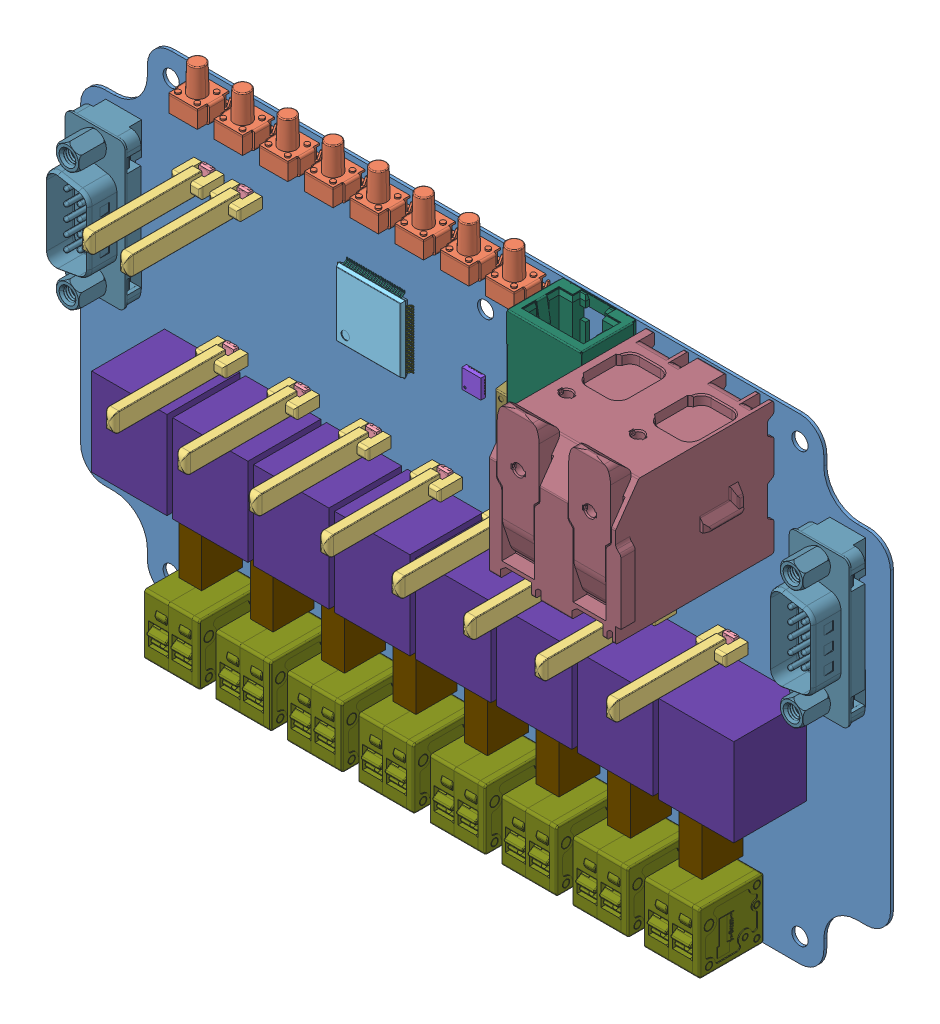
SolidWorks assembly KR-Df-01-EL-00 PCBA 2024_01_12_1, configuration Default. Lengths in mm.
Overall size (170 104.9 36.71).
192 component instances, 18 part files, 0 mates.
Components (placement in the parent):
- KR-Df-01-EL-00 PCBA 2024_01_12_1.step-1: KR-Df-01-EL-00 PCBA 2024_01_12_1.step [Default] at origin size (170 104.9 36.71)
  - Board.step-1: Board.step [Default] at origin size (170 100 0.62)
    - Open CASCADE STEP translator 7.5 3.1.1.step-1: Open CASCADE STEP translator 7.5 3.1.1.step [Default] at (0 0 -0.6237) size (170 100 0.62)
  - S607.step-1: S607.step [Default] at origin size (8.41 12.37 10.52)
    - 1-1825027-1.step-1: 1-1825027-1.step [Default] at (95 95.3 0) x (-1 0 0) z (0 1 0) size (8.41 10.52 12.37)
  - S606.step-1: S606.step [Default] at origin size (8.41 12.37 10.52)
    - 1-1825027-1.step-1: 1-1825027-1.step [Default] at (85.5 95.3 0) x (-1 0 0) z (0 1 0) size (8.41 10.52 12.37)
  - S605.step-1: S605.step [Default] at origin size (8.41 12.37 10.52)
    - 1-1825027-1.step-1: 1-1825027-1.step [Default] at (76 95.3 0) x (-1 0 0) z (0 1 0) size (8.41 10.52 12.37)
  - S604.step-1: S604.step [Default] at origin size (8.41 12.37 10.52)
    - 1-1825027-1.step-1: 1-1825027-1.step [Default] at (66.5 95.3 0) x (-1 0 0) z (0 1 0) size (8.41 10.52 12.37)
  - S603.step-1: S603.step [Default] at origin size (8.41 12.37 10.52)
    - 1-1825027-1.step-1: 1-1825027-1.step [Default] at (57 95.3 0) x (-1 0 0) z (0 1 0) size (8.41 10.52 12.37)
  - S602.step-1: S602.step [Default] at origin size (8.41 12.37 10.52)
    - 1-1825027-1.step-1: 1-1825027-1.step [Default] at (47.5 95.3 0) x (-1 0 0) z (0 1 0) size (8.41 10.52 12.37)
  - S601.step-1: S601.step [Default] at origin size (8.41 12.37 10.52)
    - 1-1825027-1.step-1: 1-1825027-1.step [Default] at (38 95.3 0) x (-1 0 0) z (0 1 0) size (8.41 10.52 12.37)
  - S600.step-1: S600.step [Default] at origin size (8.41 12.37 10.52)
    - 1-1825027-1.step-1: 1-1825027-1.step [Default] at (28.5 95.3 0) x (-1 0 0) z (0 1 0) size (8.41 10.52 12.37)
  - ME609.step-1: ME609.step [Default] at origin size (6.36 3.96 28.65)
    - BIVAR__INC_VLPR-24-1028-2_RGB8421504.step-1: BIVAR__INC_VLPR-24-1028-2_RGB8421504.step [Default] at (27 82 19.1) x (0 1 0) z (1 0 0) size (3.96 28.65 6.35)
  - ME608.step-1: ME608.step [Default] at origin size (6.36 3.96 28.65)
    - BIVAR__INC_VLPR-24-1028-2_RGB8421504.step-1: BIVAR__INC_VLPR-24-1028-2_RGB8421504.step [Default] at (35 82 19.1) x (0 1 0) z (1 0 0) size (3.96 28.65 6.35)
  - ME607.step-1: ME607.step [Default] at origin size (6.36 3.96 28.65)
    - BIVAR__INC_VLPR-24-1028-2_RGB8421504.step-1: BIVAR__INC_VLPR-24-1028-2_RGB8421504.step [Default] at (137 52 19.1) x (0 1 0) z (1 0 0) size (3.96 28.65 6.35)
  - ME606.step-1: ME606.step [Default] at origin size (6.36 3.96 28.65)
    - BIVAR__INC_VLPR-24-1028-2_RGB8421504.step-1: BIVAR__INC_VLPR-24-1028-2_RGB8421504.step [Default] at (122 52 19.1) x (0 1 0) z (1 0 0) size (3.96 28.65 6.35)
  - ME605.step-1: ME605.step [Default] at origin size (6.36 3.96 28.65)
    - BIVAR__INC_VLPR-24-1028-2_RGB8421504.step-1: BIVAR__INC_VLPR-24-1028-2_RGB8421504.step [Default] at (107 52 19.1) x (0 1 0) z (1 0 0) size (3.96 28.65 6.35)
  - ME604.step-1: ME604.step [Default] at origin size (6.36 3.96 28.65)
    - BIVAR__INC_VLPR-24-1028-2_RGB8421504.step-1: BIVAR__INC_VLPR-24-1028-2_RGB8421504.step [Default] at (92 52 19.1) x (0 1 0) z (1 0 0) size (3.96 28.65 6.35)
  - ME603.step-1: ME603.step [Default] at origin size (6.36 3.96 28.65)
    - BIVAR__INC_VLPR-24-1028-2_RGB8421504.step-1: BIVAR__INC_VLPR-24-1028-2_RGB8421504.step [Default] at (77 52 19.1) x (0 1 0) z (1 0 0) size (3.96 28.65 6.35)
  - ME602.step-1: ME602.step [Default] at origin size (6.36 3.96 28.65)
    - BIVAR__INC_VLPR-24-1028-2_RGB8421504.step-1: BIVAR__INC_VLPR-24-1028-2_RGB8421504.step [Default] at (62 52 19.1) x (0 1 0) z (1 0 0) size (3.96 28.65 6.35)
  - ME601.step-1: ME601.step [Default] at origin size (6.36 3.96 28.65)
    - BIVAR__INC_VLPR-24-1028-2_RGB8421504.step-1: BIVAR__INC_VLPR-24-1028-2_RGB8421504.step [Default] at (47 52 19.1) x (0 1 0) z (1 0 0) size (3.96 28.65 6.35)
  - ME600.step-1: ME600.step [Default] at origin size (6.36 3.96 28.65)
    - BIVAR__INC_VLPR-24-1028-2_RGB8421504.step-1: BIVAR__INC_VLPR-24-1028-2_RGB8421504.step [Default] at (32 52 19.1) x (0 1 0) z (1 0 0) size (3.96 28.65 6.35)
  - D609.step-1: D609.step [Default] at origin size (2.4 2.7 1.1)
    - IN-PI22TAT.step-1: IN-PI22TAT.step [Default] at (27 82 0) x (0 1 0) z (1 0 0) size (2.7 1.1 2.4)
  - D608.step-1: D608.step [Default] at origin size (2.4 2.7 1.1)
    - IN-PI22TAT.step-1: IN-PI22TAT.step [Default] at (35 82 0) x (0 1 0) z (1 0 0) size (2.7 1.1 2.4)
  - D607.step-1: D607.step [Default] at origin size (2.4 2.7 1.1)
    - IN-PI22TAT.step-1: IN-PI22TAT.step [Default] at (137 52 0) x (0 -1 0) z (-1 0 0) size (2.7 1.1 2.4)
  - D606.step-1: D606.step [Default] at origin size (2.4 2.7 1.1)
    - IN-PI22TAT.step-1: IN-PI22TAT.step [Default] at (122 52 0) x (0 -1 0) z (-1 0 0) size (2.7 1.1 2.4)
  - D605.step-1: D605.step [Default] at origin size (2.4 2.7 1.1)
    - IN-PI22TAT.step-1: IN-PI22TAT.step [Default] at (107 52 0) x (0 -1 0) z (-1 0 0) size (2.7 1.1 2.4)
  - D604.step-1: D604.step [Default] at origin size (2.4 2.7 1.1)
    - IN-PI22TAT.step-1: IN-PI22TAT.step [Default] at (92 52 0) x (0 -1 0) z (-1 0 0) size (2.7 1.1 2.4)
  - D603.step-1: D603.step [Default] at origin size (2.4 2.7 1.1)
    - IN-PI22TAT.step-1: IN-PI22TAT.step [Default] at (77 52 0) x (0 -1 0) z (-1 0 0) size (2.7 1.1 2.4)
  - D602.step-1: D602.step [Default] at origin size (2.4 2.7 1.1)
    - IN-PI22TAT.step-1: IN-PI22TAT.step [Default] at (62 52 0) x (0 -1 0) z (-1 0 0) size (2.7 1.1 2.4)
  - D601.step-1: D601.step [Default] at origin size (2.4 2.7 1.1)
    - IN-PI22TAT.step-1: IN-PI22TAT.step [Default] at (47 52 0) x (0 -1 0) z (-1 0 0) size (2.7 1.1 2.4)
  - D600.step-1: D600.step [Default] at origin size (2.4 2.7 1.1)
    - IN-PI22TAT.step-1: IN-PI22TAT.step [Default] at (32 52 0) x (0 -1 0) z (-1 0 0) size (2.7 1.1 2.4)
  - U500.step-1: U500.step [Default] at origin size (16 16 1.6)
    - STM32H573VIT6_RGB8421504.step-1: STM32H573VIT6_RGB8421504.step [Default] at (62 73 0) x (0 1 0) z (0 0 1) size (16 16 1.6)
      - Body.step-1: Body.step [Default] at origin size (14 14 1.5)
      - PinsArrayLR.step-1: PinsArrayLR.step [Default] at origin size (16 12.22 0.86)
      - PinsArrayTB.step-1: PinsArrayTB.step [Default] at origin size (12.22 16 0.86)
  - U200.step-1: U200.step [Default] at origin size (4 4 1)
    - 6102634304.step-1: 6102634304.step [Default] at (83 72 0) x (0 1 0) z (0 0 1) size (4 4 1)
      - Body-0.step-1: Body-0.step [Default] at (-2 -2 0) size (4 4 1)
        - Open CASCADE STEP translator 6.8 14.2.1.step-1: Open CASCADE STEP translator 6.8 14.2.1.step [Default] at origin size (4 4 1)
      - Pin_Shape.step-1: Pin_Shape.step [Default] at (-2 -1.37 0) size (0.4 0.24 0.2)
        - Open CASCADE STEP translator 6.8 14.4.1.step-1: Open CASCADE STEP translator 6.8 14.4.1.step [Default] at origin size (0.4 0.24 0.2)
      - Pin_Shape.step-2: Pin_Shape.step [Default] at (2 1.37 0) x (-1 0 0) z (0 0 1) size (0.4 0.24 0.2)
        - Open CASCADE STEP translator 6.8 14.4.1.step-1: Open CASCADE STEP translator 6.8 14.4.1.step [Default] at origin size (0.4 0.24 0.2)
      - Pin_Shape.step-3: Pin_Shape.step [Default] at (-2 -0.87 0) size (0.4 0.24 0.2)
        - Open CASCADE STEP translator 6.8 14.4.1.step-1: Open CASCADE STEP translator 6.8 14.4.1.step [Default] at origin size (0.4 0.24 0.2)
      - Pin_Shape.step-4: Pin_Shape.step [Default] at (2 0.87 0) x (-1 0 0) z (0 0 1) size (0.4 0.24 0.2)
        - Open CASCADE STEP translator 6.8 14.4.1.step-1: Open CASCADE STEP translator 6.8 14.4.1.step [Default] at origin size (0.4 0.24 0.2)
      - Pin_Shape.step-5: Pin_Shape.step [Default] at (-2 -0.37 0) size (0.4 0.24 0.2)
        - Open CASCADE STEP translator 6.8 14.4.1.step-1: Open CASCADE STEP translator 6.8 14.4.1.step [Default] at origin size (0.4 0.24 0.2)
      - Pin_Shape.step-6: Pin_Shape.step [Default] at (2 0.37 0) x (-1 0 0) z (0 0 1) size (0.4 0.24 0.2)
        - Open CASCADE STEP translator 6.8 14.4.1.step-1: Open CASCADE STEP translator 6.8 14.4.1.step [Default] at origin size (0.4 0.24 0.2)
      - Pin_Shape.step-7: Pin_Shape.step [Default] at (-2 0.13 0) size (0.4 0.24 0.2)
        - Open CASCADE STEP translator 6.8 14.4.1.step-1: Open CASCADE STEP translator 6.8 14.4.1.step [Default] at origin size (0.4 0.24 0.2)
      - Pin_Shape.step-8: Pin_Shape.step [Default] at (2 -0.13 0) x (-1 0 0) z (0 0 1) size (0.4 0.24 0.2)
        - Open CASCADE STEP translator 6.8 14.4.1.step-1: Open CASCADE STEP translator 6.8 14.4.1.step [Default] at origin size (0.4 0.24 0.2)
      - Pin_Shape.step-9: Pin_Shape.step [Default] at (-2 0.63 0) size (0.4 0.24 0.2)
        - Open CASCADE STEP translator 6.8 14.4.1.step-1: Open CASCADE STEP translator 6.8 14.4.1.step [Default] at origin size (0.4 0.24 0.2)
      - Pin_Shape.step-10: Pin_Shape.step [Default] at (2 -0.63 0) x (-1 0 0) z (0 0 1) size (0.4 0.24 0.2)
        - Open CASCADE STEP translator 6.8 14.4.1.step-1: Open CASCADE STEP translator 6.8 14.4.1.step [Default] at origin size (0.4 0.24 0.2)
      - Pin_Shape.step-11: Pin_Shape.step [Default] at (-2 1.13 0) size (0.4 0.24 0.2)
        - Open CASCADE STEP translator 6.8 14.4.1.step-1: Open CASCADE STEP translator 6.8 14.4.1.step [Default] at origin size (0.4 0.24 0.2)
      - Pin_Shape.step-12: Pin_Shape.step [Default] at (2 -1.13 0) x (-1 0 0) z (0 0 1) size (0.4 0.24 0.2)
        - Open CASCADE STEP translator 6.8 14.4.1.step-1: Open CASCADE STEP translator 6.8 14.4.1.step [Default] at origin size (0.4 0.24 0.2)
      - Pin_Shape.step-13: Pin_Shape.step [Default] at (-1.13 -2 0) x (0 1 0) z (0 0 1) size (0.4 0.24 0.2)
        - Open CASCADE STEP translator 6.8 14.4.1.step-1: Open CASCADE STEP translator 6.8 14.4.1.step [Default] at origin size (0.4 0.24 0.2)
      - Pin_Shape.step-14: Pin_Shape.step [Default] at (1.13 2 0) x (0 -1 0) z (0 0 1) size (0.4 0.24 0.2)
        - Open CASCADE STEP translator 6.8 14.4.1.step-1: Open CASCADE STEP translator 6.8 14.4.1.step [Default] at origin size (0.4 0.24 0.2)
      - Pin_Shape.step-15: Pin_Shape.step [Default] at (-0.63 -2 0) x (0 1 0) z (0 0 1) size (0.4 0.24 0.2)
        - Open CASCADE STEP translator 6.8 14.4.1.step-1: Open CASCADE STEP translator 6.8 14.4.1.step [Default] at origin size (0.4 0.24 0.2)
      - Pin_Shape.step-16: Pin_Shape.step [Default] at (0.63 2 0) x (0 -1 0) z (0 0 1) size (0.4 0.24 0.2)
        - Open CASCADE STEP translator 6.8 14.4.1.step-1: Open CASCADE STEP translator 6.8 14.4.1.step [Default] at origin size (0.4 0.24 0.2)
      - Pin_Shape.step-17: Pin_Shape.step [Default] at (-0.13 -2 0) x (0 1 0) z (0 0 1) size (0.4 0.24 0.2)
        - Open CASCADE STEP translator 6.8 14.4.1.step-1: Open CASCADE STEP translator 6.8 14.4.1.step [Default] at origin size (0.4 0.24 0.2)
      - Pin_Shape.step-18: Pin_Shape.step [Default] at (0.13 2 0) x (0 -1 0) z (0 0 1) size (0.4 0.24 0.2)
        - Open CASCADE STEP translator 6.8 14.4.1.step-1: Open CASCADE STEP translator 6.8 14.4.1.step [Default] at origin size (0.4 0.24 0.2)
      - Pin_Shape.step-19: Pin_Shape.step [Default] at (0.37 -2 0) x (0 1 0) z (0 0 1) size (0.4 0.24 0.2)
        - Open CASCADE STEP translator 6.8 14.4.1.step-1: Open CASCADE STEP translator 6.8 14.4.1.step [Default] at origin size (0.4 0.24 0.2)
      - Pin_Shape.step-20: Pin_Shape.step [Default] at (-0.37 2 0) x (0 -1 0) z (0 0 1) size (0.4 0.24 0.2)
        - Open CASCADE STEP translator 6.8 14.4.1.step-1: Open CASCADE STEP translator 6.8 14.4.1.step [Default] at origin size (0.4 0.24 0.2)
      - Pin_Shape.step-21: Pin_Shape.step [Default] at (0.87 -2 0) x (0 1 0) z (0 0 1) size (0.4 0.24 0.2)
        - Open CASCADE STEP translator 6.8 14.4.1.step-1: Open CASCADE STEP translator 6.8 14.4.1.step [Default] at origin size (0.4 0.24 0.2)
      - Pin_Shape.step-22: Pin_Shape.step [Default] at (-0.87 2 0) x (0 -1 0) z (0 0 1) size (0.4 0.24 0.2)
        - Open CASCADE STEP translator 6.8 14.4.1.step-1: Open CASCADE STEP translator 6.8 14.4.1.step [Default] at origin size (0.4 0.24 0.2)
      - Pin_Shape.step-23: Pin_Shape.step [Default] at (1.37 -2 0) x (0 1 0) z (0 0 1) size (0.4 0.24 0.2)
        - Open CASCADE STEP translator 6.8 14.4.1.step-1: Open CASCADE STEP translator 6.8 14.4.1.step [Default] at origin size (0.4 0.24 0.2)
      - Pin_Shape.step-24: Pin_Shape.step [Default] at (-1.37 2 0) x (0 -1 0) z (0 0 1) size (0.4 0.24 0.2)
        - Open CASCADE STEP translator 6.8 14.4.1.step-1: Open CASCADE STEP translator 6.8 14.4.1.step [Default] at origin size (0.4 0.24 0.2)
      - Open CASCADE STEP translator 6.8 14.1.step-1: Open CASCADE STEP translator 6.8 14.1.step [Default] at (-2 -2 0) size (0.51 0.51 0.01)
      - Thermal_Shape.step-1: Thermal_Shape.step [Default] at (-1.25 -1.25 -0.001) size (2.5 2.5 0)
  - T200.step-1: T200.step [Default] at origin size (9.3 12.8 5.68)
    - PT61018PEL.step-1: PT61018PEL.step [Default] at (99.35 78.3999 5.65) x (0 -1 0) z (1 0 0) size (12.8 5.68 9.3)
  - J400.step-1: J400.step [Default] at origin size (27.81 32.01 33.2)
    - 2616-1352.step-1: 2616-1352.step [Default] at (120.5 89.5 0) x (0 1 0) z (1 0 0) size (32.01 33.2 27.81)
  - J301.step-1: J301.step [Default] at origin size (12.55 30.81 15.4)
    - L717TSEH09POL2RM8--3DModel-STEP-533217.step-1: L717TSEH09POL2RM8--3DModel-STEP-533217.step [Default] at (167.275 53.58 0) x (0 1 0) z (1 0 0) size (30.81 15.4 12.55)
  - J300.step-1: J300.step [Default] at origin size (12.55 30.81 15.4)
    - L717TSEH09POL2RM8--3DModel-STEP-533217.step-1: L717TSEH09POL2RM8--3DModel-STEP-533217.step [Default] at (15.275 53.58 0) x (0 1 0) z (1 0 0) size (30.81 15.4 12.55)
  - P200.step-1: P200.step [Default] at origin size (16.33 18.55 13.95)
    - M-RJLSE-4X381-01T-REVT1.step-1: M-RJLSE-4X381-01T-REVT1.step [Default] at (108.9999 99.725 0) x (1 0 0) z (0 1 0) size (16.33 13.95 18.55)
  - P103.step-1: P103.step [Default] at origin size (11.62 12.71 17.41)
    - DGPS2.5R-5.0-02P-14-00Z(H).step-1: DGPS2.5R-5.0-02P-14-00Z(H).step [Default] at (76.8 0.1 0) x (1 0 0) z (0 -1 0) size (11.62 17.41 12.71)
  - P101.step-1: P101.step [Default] at origin size (11.62 12.71 17.41)
    - DGPS2.5R-5.0-02P-14-00Z(H).step-1: DGPS2.5R-5.0-02P-14-00Z(H).step [Default] at (46.8 0.1 0) x (1 0 0) z (0 -1 0) size (11.62 17.41 12.71)
  - P106.step-1: P106.step [Default] at origin size (11.62 12.71 17.41)
    - DGPS2.5R-5.0-02P-14-00Z(H).step-1: DGPS2.5R-5.0-02P-14-00Z(H).step [Default] at (121.8 0.1 0) x (1 0 0) z (0 -1 0) size (11.62 17.41 12.71)
  - P104.step-1: P104.step [Default] at origin size (11.62 12.71 17.41)
    - DGPS2.5R-5.0-02P-14-00Z(H).step-1: DGPS2.5R-5.0-02P-14-00Z(H).step [Default] at (91.8 0.1 0) x (1 0 0) z (0 -1 0) size (11.62 17.41 12.71)
  - P100.step-1: P100.step [Default] at origin size (11.62 12.71 17.41)
    - DGPS2.5R-5.0-02P-14-00Z(H).step-1: DGPS2.5R-5.0-02P-14-00Z(H).step [Default] at (31.8 0.1 0) x (1 0 0) z (0 -1 0) size (11.62 17.41 12.71)
  - P107.step-1: P107.step [Default] at origin size (11.62 12.71 17.41)
    - DGPS2.5R-5.0-02P-14-00Z(H).step-1: DGPS2.5R-5.0-02P-14-00Z(H).step [Default] at (136.8 0.1 0) x (1 0 0) z (0 -1 0) size (11.62 17.41 12.71)
  - P105.step-1: P105.step [Default] at origin size (11.62 12.71 17.41)
    - DGPS2.5R-5.0-02P-14-00Z(H).step-1: DGPS2.5R-5.0-02P-14-00Z(H).step [Default] at (106.8 0.1 0) x (1 0 0) z (0 -1 0) size (11.62 17.41 12.71)
  - P102.step-1: P102.step [Default] at origin size (11.62 12.71 17.41)
    - DGPS2.5R-5.0-02P-14-00Z(H).step-1: DGPS2.5R-5.0-02P-14-00Z(H).step [Default] at (61.8 0.1 0) x (1 0 0) z (0 -1 0) size (11.62 17.41 12.71)
  - K104.step-1: K104.step [Default] at origin size (15.8 18.4 15.29)
    - 6227875488.step-1: 6227875488.step [Default] at (93.5 39.55 0) size (15.8 18.4 15.29)
      - Extruded.step-1: Extruded.step [Default] at origin size (15.8 18.4 15.29)
  - K101.step-1: K101.step [Default] at origin size (15.8 18.4 15.29)
    - 6227875488.step-1: 6227875488.step [Default] at (42.5 39.55 0) size (15.8 18.4 15.29)
      - Extruded.step-1: Extruded.step [Default] at origin size (15.8 18.4 15.29)
  - K106.step-1: K106.step [Default] at origin size (15.8 18.4 15.29)
    - 6227875488.step-1: 6227875488.step [Default] at (127.5 39.55 0) size (15.8 18.4 15.29)
      - Extruded.step-1: Extruded.step [Default] at origin size (15.8 18.4 15.29)
  - K103.step-1: K103.step [Default] at origin size (15.8 18.4 15.29)
    - 6227875488.step-1: 6227875488.step [Default] at (76.5 39.55 0) size (15.8 18.4 15.29)
      - Extruded.step-1: Extruded.step [Default] at origin size (15.8 18.4 15.29)
  - K100.step-1: K100.step [Default] at origin size (15.8 18.4 15.29)
    - 6227875488.step-1: 6227875488.step [Default] at (25.5 39.55 0) size (15.8 18.4 15.29)
      - Extruded.step-1: Extruded.step [Default] at origin size (15.8 18.4 15.29)
  - K107.step-1: K107.step [Default] at origin size (15.8 18.4 15.29)
    - 6227875488.step-1: 6227875488.step [Default] at (144.5 39.55 0) size (15.8 18.4 15.29)
      - Extruded.step-1: Extruded.step [Default] at origin size (15.8 18.4 15.29)
  - K105.step-1: K105.step [Default] at origin size (15.8 18.4 15.29)
    - 6227875488.step-1: 6227875488.step [Default] at (110.5 39.55 0) size (15.8 18.4 15.29)
      - Extruded.step-1: Extruded.step [Default] at origin size (15.8 18.4 15.29)
  - K102.step-1: K102.step [Default] at origin size (15.8 18.4 15.29)
    - 6227875488.step-1: 6227875488.step [Default] at (59.5 39.55 0) size (15.8 18.4 15.29)
      - Extruded.step-1: Extruded.step [Default] at origin size (15.8 18.4 15.29)
  - F103.step-1: F103.step [Default] at origin size (4.8 14.7 8.6)
    - 6227873168.step-1: 6227873168.step [Default] at (76.6 21 0) size (4.8 14.7 8.6)
      - Extruded-1.step-1: Extruded-1.step [Default] at origin size (4.8 14.7 8.6)
  - F101.step-1: F101.step [Default] at origin size (4.8 14.7 8.6)
    - 6227873168.step-1: 6227873168.step [Default] at (46.6 21 0) size (4.8 14.7 8.6)
      - Extruded-1.step-1: Extruded-1.step [Default] at origin size (4.8 14.7 8.6)
  - F106.step-1: F106.step [Default] at origin size (4.8 14.7 8.6)
    - 6227873168.step-1: 6227873168.step [Default] at (121.6 21 0) size (4.8 14.7 8.6)
      - Extruded-1.step-1: Extruded-1.step [Default] at origin size (4.8 14.7 8.6)
  - F104.step-1: F104.step [Default] at origin size (4.8 14.7 8.6)
    - 6227873168.step-1: 6227873168.step [Default] at (91.6 21 0) size (4.8 14.7 8.6)
      - Extruded-1.step-1: Extruded-1.step [Default] at origin size (4.8 14.7 8.6)
  - F100.step-1: F100.step [Default] at origin size (4.8 14.7 8.6)
    - 6227873168.step-1: 6227873168.step [Default] at (31.6 21 0) size (4.8 14.7 8.6)
      - Extruded-1.step-1: Extruded-1.step [Default] at origin size (4.8 14.7 8.6)
  - F107.step-1: F107.step [Default] at origin size (4.8 14.7 8.6)
    - 6227873168.step-1: 6227873168.step [Default] at (136.6 21 0) size (4.8 14.7 8.6)
      - Extruded-1.step-1: Extruded-1.step [Default] at origin size (4.8 14.7 8.6)
  - F105.step-1: F105.step [Default] at origin size (4.8 14.7 8.6)
    - 6227873168.step-1: 6227873168.step [Default] at (106.6 21 0) size (4.8 14.7 8.6)
      - Extruded-1.step-1: Extruded-1.step [Default] at origin size (4.8 14.7 8.6)
  - F102.step-1: F102.step [Default] at origin size (4.8 14.7 8.6)
    - 6227873168.step-1: 6227873168.step [Default] at (61.6 21 0) size (4.8 14.7 8.6)
      - Extruded-1.step-1: Extruded-1.step [Default] at origin size (4.8 14.7 8.6)
